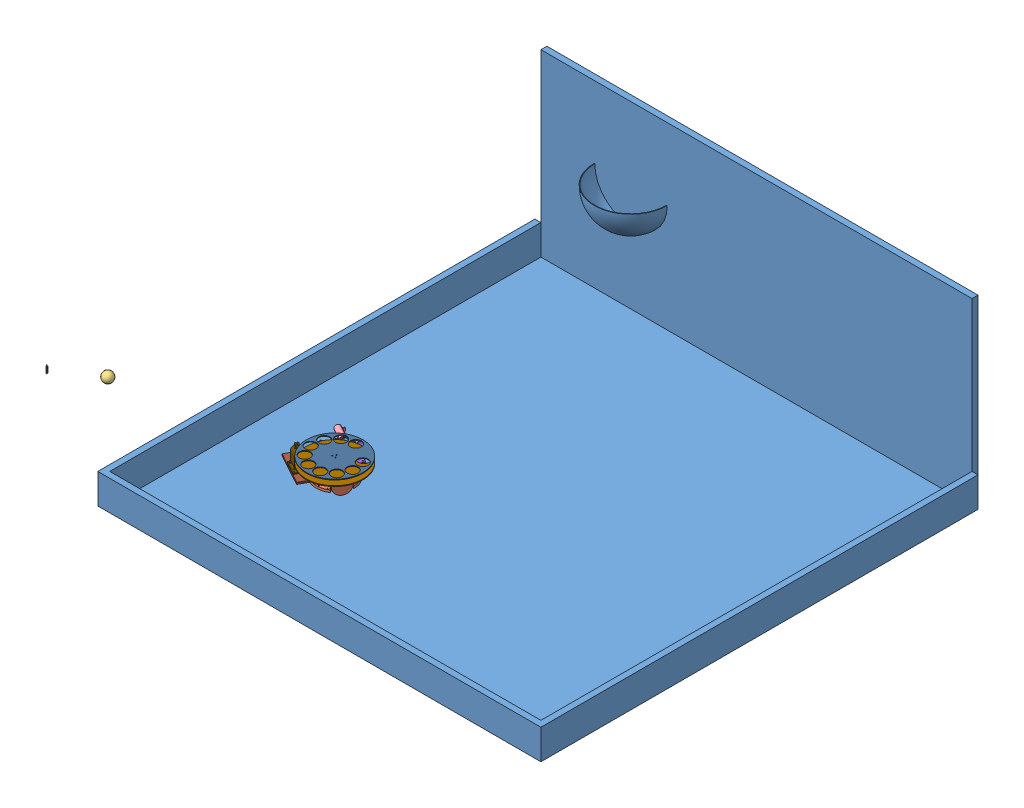
SolidWorks assembly mechatronics_project_assembly, configuration Default. Lengths in mm.
Overall size (2432.99 787.4 1879.6).
28 component instances, 18 part files, 34 mates.
Components (placement in the parent):
- basketball_court-1: basketball_court [Default] at (-553.2872 642.2457 2335.0048) size (1879.6 787.4 1879.6)
- RSLKRobot-1: RSLKRobot [Default] at (-249.6974 683.1397 1761.6145) x (0.878002 0 0.478656) z (-0.478656 0 0.878002) size (153.54 68.83 162.51)
- ball-1: ball [Default] at (-888.5529 810.9089 2008.0395) x (0.301423 0 0.953491) z (0.953491 0 -0.301423) size (42.67 42.67 42.67)
- dc_motor-1: dc_motor [Default] at (-228.6195 796.7974 1693.0358) x (0.878002 0 0.478656) z (0 1 0) size (75 32.2 24.4) (hidden)
- wheel_for_flywheel-1: wheel_for_flywheel [Default] at (-134.3221 796.7974 1744.4435) x (-0.878002 0 -0.478656) z (-0.346778 -0.689293 0.636097) size (35 23.46 23.46)
- threaded rods-1: threaded rods [Default] at (-1129.4136 712.5154 2025.6498) size (5.33 31.75 4.83)
- fitting_for_dc_motor_shaft-1: fitting_for_dc_motor_shaft [Default] at (-167.1594 796.7974 1726.5417) x (0.878002 0 0.478656) z (-0.346778 -0.689293 0.636097) size (6.1 11 11) (hidden)
- ramp2-1: ramp2 [Default] at (-149.5972 769.8741 1736.111) x (-0.878002 0 -0.478656) z (0.478656 0 -0.878002) size (68 66.31 166.56)
- bottom_plate-1: bottom_plate [Default] at (-43.9155 855.9574 1890.2252) x (0.847405 0 0.530948) z (-0.530948 0 0.847405) size (240 3.17 240)
- top_plate-1: top_plate [Default] at (-43.9155 880.1324 1890.2252) x (1 0 0.000774) z (-0.000774 0 1) size (240 3.17 240)
- RSLKBasePlate-1: RSLKBasePlate [Default] at (-216.6775 737.3941 1801.4719) x (0.878002 0 0.478656) z (-0.478656 0 0.878002) size (154.69 6.35 228.6)
- stepper_motor_shaft-1: stepper_motor_shaft [Default] at (-43.9155 856.8124 1890.2252) x (1 0 0.000774) z (-0.000774 0 1) size (25.4 23.32 25.4)
- stepper_motor-1: stepper_motor [Default] at (-43.9155 836.6534 1890.2252) x (0.847405 0 0.530948) z (-0.530948 0 0.847405) size (41.52 19.3 29.63)
- wheel_pin-1: wheel_pin [Default] at (-125.54 796.9741 1749.2262) x (-0.346778 -0.689293 0.636097) z (-0.878002 0 -0.478656) size (15 15 22)
- RSLKAss-1: RSLKAss [Default] at (-124.7425 606.4019 1634.0212) x (0.878002 0 0.478656) z (-0.478656 0 0.878002) size (154.69 145.83 228.6)
  - RSLKRobot-1: RSLKRobot [Default] at (-48.6373 76.7378 171.8377) size (153.54 68.83 162.51)
  - 1inHexSpacer-1: 1inHexSpacer [Default] at (-16.032 111.7898 197.7688) x (0.5 0 0.866025) z (0.866025 0 -0.5) size (5.57 31.75 4.83)
  - 1inHexSpacer-3: 1inHexSpacer [Default] at (67.9824 111.7898 197.7688) x (0.5 0 0.866025) z (0.866025 0 -0.5) size (5.57 31.75 4.83)
  - .75inHexSpacer-1: .75inHexSpacer [Default] at (52.5182 129.7222 100.832) x (1 0 0) z (0 0 -1) size (5.57 25.4 4.83)
  - .75inHexSpacer-2: .75inHexSpacer [Default] at (-0.5678 129.7222 191.0274) x (1 0 0) z (0 0 -1) size (5.57 25.4 4.83)
  - .75inHexSpacer-3: .75inHexSpacer [Default] at (52.5182 129.7222 191.0274) x (1 0 0) z (0 0 -1) size (5.57 25.4 4.83)
  - .75inHexSpacer-4: .75inHexSpacer [Default] at (-0.5678 129.7222 100.832) x (1 0 0) z (0 0 -1) size (5.57 25.4 4.83)
  - 1inHexSpacer-4: 1inHexSpacer [Default] at (-2.6646 111.7898 204.6548) x (0.5 0 0.866025) z (0.866025 0 -0.5) size (5.57 31.75 4.83)
  - 1inHexSpacer-5: 1inHexSpacer [Default] at (54.615 111.7898 204.6548) x (0.5 0 0.866025) z (0.866025 0 -0.5) size (5.57 31.75 4.83)
  - RSLKSpacePlate-1: RSLKSpacePlate [Default] at (67.9824 114.9648 197.7688) x (-1 0 0) z (0 0 -1) size (108.14 17.78 33.54)
  - RSLKBasePlate-2: RSLKBasePlate [Default] at (-0.5678 129.7222 191.276) size (154.69 6.35 228.6)
  - MotorMount-1: MotorMount [Default] at (-2.3457 181.0722 248.282) x (0 -1 0) z (1 0 0) size (71 58 63)
- dc_motor-2: dc_motor [Default] at (-190.7686 787.4741 1880.8066) x (-0.878002 0 -0.478656) z (0.182775 -0.924225 -0.335265) size (75 32.2 24.4)
Mates (geometry in assembly coordinates):
- Tangent1: tangent anti-aligned: plane of basketball_court-1 through (-553.2872 667.6457 2335.0048) normal (0 1 0); cylinder of RSLKRobot-1 through (-234.2802 702.0627 1728.8241) axis (0.878002 0 0.478656) radius 34.417
- Tangent2: tangent anti-aligned: plane of basketball_court-1 through (-553.2872 667.6457 2335.0048) normal (0 1 0); cylinder of RSLKRobot-1 through (-99.4691 702.0627 1802.3184) axis (-0.878002 0 -0.478656) radius 34.417
- Parallel3: parallel aligned: plane of basketball_court-1 through (-553.2872 667.6457 2335.0048) normal (0 1 0); plane of RSLKRobot-1 through (-249.6974 692.7917 1761.6145) normal (0 1 0)
- Concentric12: concentric aligned: cylinder of dc_motor-1 through (-162.7694 796.7974 1728.935) axis (-0.878002 0 -0.478656) radius 2; cylinder of fitting_for_dc_motor_shaft-1 through (-161.8914 796.7974 1729.4137) axis (-0.878002 0 -0.478656) radius 2.075
- Coincident13: coincident anti-aligned: plane of dc_motor-1 through (-162.7694 796.7974 1728.935) normal (0.878002 0 0.478656); plane of fitting_for_dc_motor_shaft-1 through (-162.7694 796.7974 1728.935) normal (-0.878002 0 -0.478656)
- Coincident14: coincident anti-aligned: plane of wheel_for_flywheel-1 through (-156.1387 793.263 1732.65) normal (0.346778 0.689293 -0.636097); plane of fitting_for_dc_motor_shaft-1 through (-163.4954 796.8854 1732.5648) normal (-0.346778 -0.689293 0.636097)
- Coincident15: coincident anti-aligned: plane of wheel_for_flywheel-1 through (-154.3181 796.8818 1729.3105) normal (-0.329935 0.724482 0.605201); plane of fitting_for_dc_motor_shaft-1 through (-161.8457 793.263 1729.5388) normal (0.329935 -0.724482 -0.605201)
- Coincident18: coincident anti-aligned: plane of wheel_for_flywheel-1 through (-165.0522 796.7974 1727.6905) normal (-0.878002 0 -0.478656); plane of fitting_for_dc_motor_shaft-1 through (-165.0522 796.7974 1727.6905) normal (0.878002 0 0.478656)
- Parallel4: parallel aligned: line of RSLKRobot-1 through (-220.2096 715.6517 1802.5116) axis (0.878002 0 0.478656); line of ramp2-1 through (-152.1645 742.4741 1676.0555) axis (0.878002 0 0.478656)
- Concentric16: concentric aligned: cylinder of bottom_plate-1 through (-43.9155 859.1324 1890.2252) axis (0 -1 0) radius 120; cylinder of top_plate-1 through (-43.9155 883.3074 1890.2252) axis (0 -1 0) radius 120
- Distance1: distance = 21 mm anti-aligned: plane of bottom_plate-1 through (-43.9155 859.1324 1890.2252) normal (0 1 0); plane of top_plate-1 through (-43.9155 880.1324 1890.2252) normal (0 -1 0)
- Concentric18: concentric anti-aligned: cylinder of RSLKRobot-1 through (-216.6775 715.6517 1801.4719) axis (0 1 0) radius 1.5875; cylinder of RSLKBasePlate-1 through (-216.6775 743.7441 1801.4719) axis (0 -1 0) radius 2.2225
- Distance2: distance = 20.32 mm anti-aligned: plane of RSLKRobot-1 through (-249.6974 717.0741 1761.6145) normal (0 1 0); plane of RSLKBasePlate-1 through (-216.6775 737.3941 1801.4719) normal (0 -1 0)
- Concentric19: concentric aligned: cylinder of top_plate-1 through (-43.9096 883.3074 1882.6052) axis (0 -1 0) radius 2; cylinder of stepper_motor_shaft-1 through (-43.9096 880.1324 1882.6052) axis (0 -1 0) radius 1.875
- Concentric20: concentric aligned: cylinder of top_plate-1 through (-37.3193 883.3074 1894.0403) axis (0 -1 0) radius 2; cylinder of stepper_motor_shaft-1 through (-37.3193 880.1324 1894.0403) axis (0 -1 0) radius 1.875
- Coincident22: coincident anti-aligned: plane of top_plate-1 through (-43.9155 880.1324 1890.2252) normal (0 -1 0); plane of stepper_motor_shaft-1 through (-43.9155 880.1324 1890.2252) normal (0 1 0)
- Concentric21: concentric aligned: cylinder of bottom_plate-1 through (-43.9155 859.1324 1890.2252) axis (0 -1 0) radius 5; cylinder of stepper_motor-1 through (-43.9155 855.9574 1890.2252) axis (0 -1 0) radius 13.97
- Coincident23: coincident anti-aligned: plane of bottom_plate-1 through (-43.9155 855.9574 1890.2252) normal (0 -1 0); plane of stepper_motor-1 through (-43.9155 855.9574 1890.2252) normal (0 1 0)
- Concentric22: concentric aligned: cylinder of bottom_plate-1 through (-58.7451 859.1324 1880.9336) axis (0 -1 0) radius 2; cylinder of stepper_motor-1 through (-58.7451 855.9574 1880.9336) axis (0 -1 0) radius 1.75
- Parallel5: parallel aligned: line of RSLKRobot-1 through (-220.2096 717.0741 1802.5116) axis (0.878002 0 0.478656); line of RSLKBasePlate-1 through (-303.0935 743.7441 1853.8548) axis (0.878002 0 0.478656)
- Coincident24: coincident anti-aligned: plane of wheel_for_flywheel-1 through (-142.1485 798.693 1737.9077) normal (-0.346778 -0.689293 0.636097); plane of wheel_pin-1 through (-143.0558 800.6853 1739.572) normal (0.346778 0.689293 -0.636097)
- Coincident25: coincident anti-aligned: plane of wheel_for_flywheel-1 through (-144.0094 798.7897 1741.3212) normal (0.329935 -0.724482 -0.605201); plane of wheel_pin-1 through (-143.0558 800.6853 1739.572) normal (-0.329935 0.724482 0.605201)
- Coincident26: coincident anti-aligned: plane of wheel_for_flywheel-1 through (-134.3221 796.7974 1744.4435) normal (0.878002 0 0.478656); plane of wheel_pin-1 through (-134.32 796.9741 1744.4396) normal (-0.878002 0 -0.478656)
- Concentric29: concentric aligned: cylinder of ramp2-1 through (-173.6545 796.9741 1722.9958) axis (0.878002 0 0.478656) radius 4.5; cylinder of wheel_pin-1 through (-134.32 796.9741 1744.4396) axis (0.878002 0 0.478656) radius 4.4
- Coincident27: coincident anti-aligned: plane of ramp2-1 through (-136.1411 794.4741 1768.6719) normal (0.878002 0 0.478656); plane of wheel_pin-1 through (-125.54 796.9741 1749.2262) normal (-0.878002 0 -0.478656)
- Concentric30: concentric anti-aligned: cylinder of RSLKAss-1/MotorMount-1 through (-190.3296 787.4741 1881.0459) axis (-0.878002 0 -0.478656) radius 13.5; cylinder of dc_motor-2 through (-245.6438 787.4741 1850.8905) axis (0.878002 0 0.478656) radius 12.2
- Coincident28: coincident aligned: plane of RSLKAss-1/MotorMount-1 through (-245.6438 787.4741 1850.8905) normal (-0.878002 0 -0.478656); plane of dc_motor-2 through (-245.6438 787.4741 1850.8905) normal (-0.878002 0 -0.478656)
- Parallel6: parallel aligned: plane of ramp2-1 through (-204.1001 744.4741 1765.0538) normal (-0.878002 0 -0.478656); plane of RSLKAss-1/RSLKBasePlate-2 through (-193.7917 742.4741 1653.3618) normal (-0.878002 0 -0.478656)
- Parallel7: parallel aligned: plane of ramp2-1 through (-154.7985 744.4741 1674.6196) normal (0.478656 0 -0.878002); plane of RSLKAss-1/RSLKBasePlate-2 through (-193.7917 742.4741 1653.3618) normal (0.478656 0 -0.878002)
- Parallel8: parallel anti-aligned: plane of basketball_court-1 through (-553.2872 667.6457 2335.0048) normal (0 1 0); plane of RSLKAss-1/RSLKRobot-1 through (-249.6974 683.1397 1761.6145) normal (0 -1 0)
- Coincident29: coincident anti-aligned: plane of ramp2-1 through (-149.5972 742.4741 1736.111) normal (0 -1 0); plane of RSLKAss-1/RSLKBasePlate-2 through (-216.7965 742.4741 1801.6902) normal (0 1 0)
- Coincident30: coincident aligned: plane of ramp2-1 through (-154.7985 744.4741 1674.6196) normal (0.478656 0 -0.878002); plane of RSLKAss-1/RSLKBasePlate-2 through (-193.7917 742.4741 1653.3618) normal (0.478656 0 -0.878002)
- Coincident31: coincident aligned: plane of RSLKRobot-1 through (-234.2802 702.0627 1728.8241) normal (-0.878002 0 -0.478656); plane of RSLKAss-1/RSLKRobot-1 through (-234.2802 702.0627 1728.8241) normal (-0.878002 0 -0.478656)
- Concentric32: concentric aligned: cylinder of RSLKRobot-1 through (-234.2802 702.0627 1728.8241) axis (0.878002 0 0.478656) radius 34.417; cylinder of RSLKAss-1/RSLKRobot-1 through (-234.2802 702.0627 1728.8241) axis (0.878002 0 0.478656) radius 34.417
